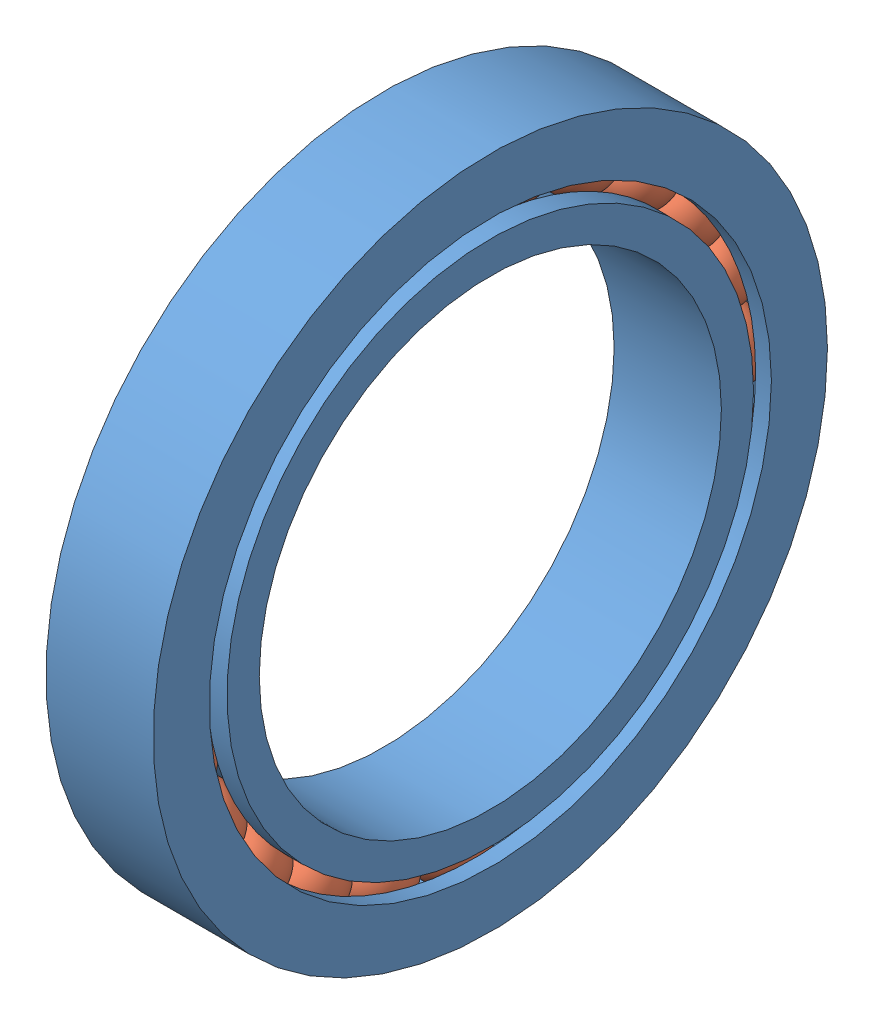
SolidWorks assembly Balero, configuration Default. Lengths in mm.
Overall size (45.77 288.01 288.01).
25 component instances, 2 part files, 1 mates.
Components (placement in the parent):
- chumacera-1-1: chumacera-1 [Default] at origin size (45.77 287.84 287.84)
- chumacera-2-1: chumacera-2 [Default] at (1.0292 105.4621 -58.212) x (0.394614 -0.587266 0.706681) z (-0.912678 -0.339487 0.227523) size (30 30 30)
- chumacera-2-2: chumacera-2 [Default] at (1.0292 116.9349 -28.9329) x (0.394614 -0.750158 0.530605) z (-0.912678 -0.386807 0.131905) size (30 30 30)
- chumacera-2-3: chumacera-2 [Default] at (1.0292 120.4389 2.318) x (0.394614 -0.861928 0.31837) z (-0.912678 -0.407766 0.027297) size (30 30 30)
- chumacera-2-4: chumacera-2 [Default] at (1.0292 115.7351 33.4108) x (0.394614 -0.914959 0.084439) z (-0.912678 -0.400937 -0.07917) size (30 30 30)
- chumacera-2-5: chumacera-2 [Default] at (1.0292 103.1441 62.2268) x (0.394614 -0.905637 -0.155247) z (-0.912678 -0.366785 -0.180243) size (30 30 30)
- chumacera-2-6: chumacera-2 [Default] at (1.0292 83.5241 86.8022) x (0.394614 -0.834597 -0.384353) z (-0.912678 -0.307636 -0.269032) size (30 30 30)
- chumacera-2-7: chumacera-2 [Default] at (1.0292 58.212 105.4621) x (0.394614 -0.706681 -0.587266) z (-0.912678 -0.227523 -0.339487) size (30 30 30)
- chumacera-2-8: chumacera-2 [Default] at (1.0292 28.9329 116.9349) x (0.394614 -0.530605 -0.750158) z (-0.912678 -0.131905 -0.386807) size (30 30 30)
- chumacera-2-9: chumacera-2 [Default] at (1.0292 -2.318 120.4389) x (0.394614 -0.31837 -0.861928) z (-0.912678 -0.027297 -0.407766) size (30 30 30)
- chumacera-2-10: chumacera-2 [Default] at (1.0292 -33.4108 115.7351) x (0.394614 -0.084439 -0.914959) z (-0.912678 0.07917 -0.400937) size (30 30 30)
- chumacera-2-11: chumacera-2 [Default] at (1.0292 -62.2268 103.1441) x (0.394614 0.155247 -0.905637) z (-0.912678 0.180243 -0.366785) size (30 30 30)
- chumacera-2-12: chumacera-2 [Default] at (1.0292 -86.8022 83.5241) x (0.394614 0.384353 -0.834597) z (-0.912678 0.269032 -0.307636) size (30 30 30)
- chumacera-2-13: chumacera-2 [Default] at (1.0292 -105.4621 58.212) x (0.394614 0.587266 -0.706681) z (-0.912678 0.339487 -0.227523) size (30 30 30)
- chumacera-2-14: chumacera-2 [Default] at (1.0292 -116.9349 28.9329) x (0.394614 0.750158 -0.530605) z (-0.912678 0.386807 -0.131905) size (30 30 30)
- chumacera-2-15: chumacera-2 [Default] at (1.0292 -120.4389 -2.318) x (0.394614 0.861928 -0.31837) z (-0.912678 0.407766 -0.027297) size (30 30 30)
- chumacera-2-16: chumacera-2 [Default] at (1.0292 -115.7351 -33.4108) x (0.394614 0.914959 -0.084439) z (-0.912678 0.400937 0.07917) size (30 30 30)
- chumacera-2-17: chumacera-2 [Default] at (1.0292 -103.1441 -62.2268) x (0.394614 0.905637 0.155247) z (-0.912678 0.366785 0.180243) size (30 30 30)
- chumacera-2-18: chumacera-2 [Default] at (1.0292 -83.5241 -86.8022) x (0.394614 0.834597 0.384353) z (-0.912678 0.307636 0.269032) size (30 30 30)
- chumacera-2-19: chumacera-2 [Default] at (1.0292 -58.212 -105.4621) x (0.394614 0.706681 0.587266) z (-0.912678 0.227523 0.339487) size (30 30 30)
- chumacera-2-20: chumacera-2 [Default] at (1.0292 -28.9329 -116.9349) x (0.394614 0.530605 0.750158) z (-0.912678 0.131905 0.386807) size (30 30 30)
- chumacera-2-21: chumacera-2 [Default] at (1.0292 2.318 -120.4389) x (0.394614 0.31837 0.861928) z (-0.912678 0.027297 0.407766) size (30 30 30)
- chumacera-2-22: chumacera-2 [Default] at (1.0292 33.4108 -115.7351) x (0.394614 0.084439 0.914959) z (-0.912678 -0.07917 0.400937) size (30 30 30)
- chumacera-2-23: chumacera-2 [Default] at (1.0292 62.2268 -103.1441) x (0.394614 -0.155247 0.905637) z (-0.912678 -0.180243 0.366785) size (30 30 30)
- chumacera-2-24: chumacera-2 [Default] at (1.0292 86.8022 -83.5241) x (0.394614 -0.384353 0.834597) z (-0.912678 -0.269032 0.307636) size (30 30 30)
Mates (geometry in assembly coordinates):
- Tangent1: tangent: torus of chumacera-1-1; sphere of chumacera-2-1
